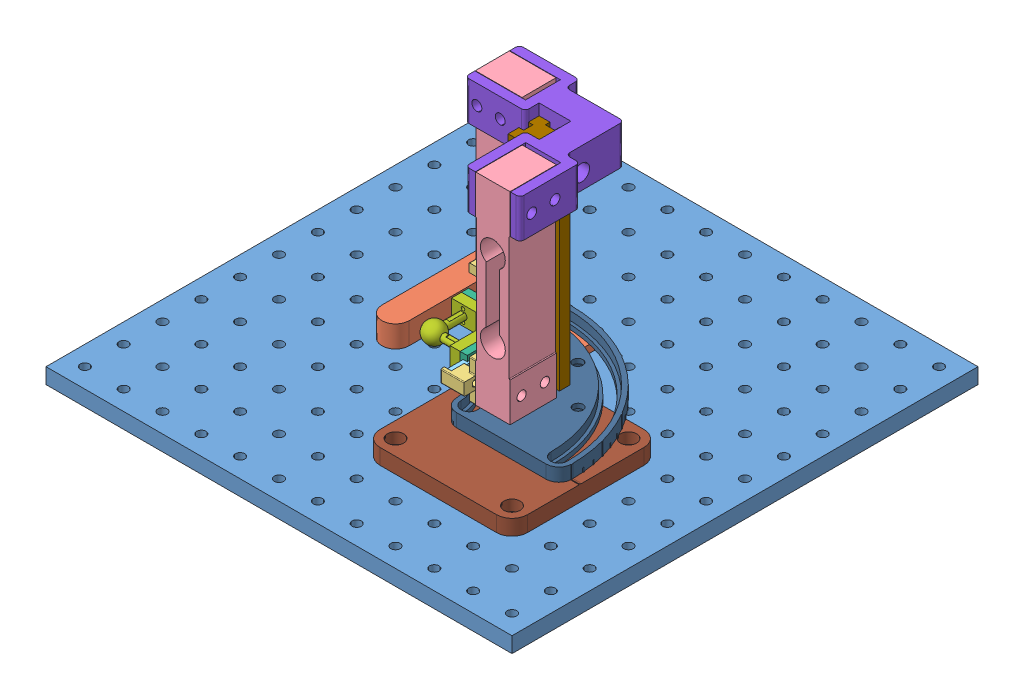
SolidWorks assembly ASM3, configuration 기본. Lengths in mm.
Overall size (300 175.5 300).
15 component instances, 11 part files, 49 mates.
Components (placement in the parent):
- platform-1: platform [기본] at (-708.9249 -138.0932 300) size (300 10 300)
- finger_model-1: finger_model [기본] at (-721.4249 -128.0932 287.5) size (60 55 113.75)
- linear_guide_holder_vertical_axis-1: linear_guide_holder_vertical_axis [기본] at (-705.2882 -80.0932 312.2502) x (0 1 0) z (0.00273 0 0.999996) size (25 45 15)
- Loadcell-1: Loadcell [기본] at (-720.3182 -27.5932 301.2911) x (0 1 0) z (0.999996 0 -0.00273) size (130 22 30)
- linear_guide_holder_vertical_axis-2: linear_guide_holder_vertical_axis [기본] at (-663.6751 -80.0932 353.6367) x (0 -1 0) z (-0.999996 0 0.00273) size (25 45 15)
- Loadcell-2: Loadcell [기본] at (-652.7161 -27.5932 338.6068) x (0 1 0) z (0.00273 0 0.999996) size (130 22 30)
- linear_guide_part1-1: linear_guide_part1 [기본] at (-678.175 -80.0932 353.6763) x (-0.00273 0 -0.999996) z (0 -1 0) size (40 4 5)
- linear_guide_part2-1: linear_guide_part2 [기본] at (-675.575 -80.0932 353.6692) x (0.00273 0 0.999996) z (0 -1 0) size (17 4.6 12)
- linear_guide_part1-2: linear_guide_part1 [기본] at (-705.2595 -80.0932 322.7501) x (-0.999996 0 0.00273) z (0 1 0) size (40 4 5)
- linear_guide_part2-2: linear_guide_part2 [기본] at (-705.2557 -80.0932 324.1501) x (0.999996 0 -0.00273) z (0 -1 0) size (17 4.6 12)
- contact_part_vertical-1: contact_part_vertical [기본] at (-705.1749 -80.0932 353.75) x (-0.999996 0 0.00273) z (0 1 0) size (33.5 33.5 13)
- Loadcell_holder_vertical_part1-1: Loadcell_holder_vertical_part1 [기본] at (-652.8184 12.4068 301.1069) x (-0.00273 0 -0.999996) z (0.999996 0 -0.00273) size (85 25 85)
- profile_20x20x140-1: profile_20x20x140 [기본] at (-671.5172 -109.5932 319.908) x (-0.00273 0 -0.999996) z (0.999996 0 -0.00273) size (20 140 20)
- rotary_guide_part1-1: rotary_guide_part1 [기본] at (-705.1749 -118.0932 353.75) x (-0.00273 0 -0.999996) z (0.999996 0 -0.00273) size (96.75 8.5 96.75)
- rotary_guide_part2-1: rotary_guide_part2 [기본] at (-705.1749 -128.0932 353.75) x (0 0 -1) z (1 0 0) size (95 10.5 95)
Mates (geometry in assembly coordinates):
- 동심1: concentric aligned: cylinder of platform-1 through (-696.4249 -128.0932 287.5) axis (0 -1 0) radius 3; cylinder of finger_model-1 through (-696.4249 -123.0932 287.5) axis (0 -1 0) radius 3
- 동심2: concentric aligned: cylinder of platform-1 through (-746.4249 -128.0932 287.5) axis (0 -1 0) radius 3; cylinder of finger_model-1 through (-746.4249 -123.0932 287.5) axis (0 -1 0) radius 3
- 일치1: coincident anti-aligned: plane of platform-1 through (-708.9249 -128.0932 300) normal (0 1 0); plane of finger_model-1 through (-721.4249 -128.0932 287.5) normal (0 -1 0)
- 일치2: coincident anti-aligned: plane of linear_guide_holder_vertical_axis-1 through (-705.2882 -80.0932 312.2502) normal (-0.00273 0 -0.999996); plane of Loadcell-1 through (-690.2883 -92.5932 312.2092) normal (0.00273 0 0.999996)
- 동심3: concentric anti-aligned: cylinder of linear_guide_holder_vertical_axis-1 through (-712.7773 -80.0932 316.2706) axis (-0.00273 0 -0.999996) radius 3.2; cylinder of Loadcell-1 through (-712.8714 -80.0932 281.7855) axis (0.00273 0 0.999996) radius 3
- 동심4: concentric anti-aligned: cylinder of linear_guide_holder_vertical_axis-1 through (-697.7773 -80.0932 316.2297) axis (-0.00273 0 -0.999996) radius 3.2; cylinder of Loadcell-1 through (-697.8714 -80.0932 281.7445) axis (0.00273 0 0.999996) radius 3
- 평행2: parallel anti-aligned: plane of platform-1 through (-708.9249 -128.0932 300) normal (0 1 0); plane of Loadcell-1 through (-690.2883 -92.5932 312.2092) normal (0 -1 0)
- 평행3: parallel anti-aligned: plane of platform-1 through (-708.9249 -128.0932 300) normal (0 1 0); plane of Loadcell-2 through (-663.6341 -92.5932 368.6367) normal (0 -1 0)
- 동심5: concentric anti-aligned: cylinder of linear_guide_holder_vertical_axis-2 through (-667.6546 -80.0932 361.1476) axis (0.999996 0 -0.00273) radius 3.2; cylinder of Loadcell-2 through (-633.1694 -80.0932 361.0535) axis (-0.999996 0 0.00273) radius 3
- 동심6: concentric anti-aligned: cylinder of linear_guide_holder_vertical_axis-2 through (-667.6955 -80.0932 346.1477) axis (0.999996 0 -0.00273) radius 3.2; cylinder of Loadcell-2 through (-633.2104 -80.0932 346.0535) axis (-0.999996 0 0.00273) radius 3
- 일치7: coincident anti-aligned: plane of linear_guide_holder_vertical_axis-2 through (-663.6751 -80.0932 353.6367) normal (0.999996 0 -0.00273); plane of Loadcell-2 through (-663.6341 -92.5932 368.6367) normal (-0.999996 0 0.00273)
- 동심7: concentric anti-aligned: cylinder of linear_guide_holder_vertical_axis-2 through (-674.216 -80.0932 338.6654) axis (0.999996 0 -0.00273) radius 1.15; cylinder of linear_guide_part1-1 through (-674.216 -80.0932 338.6654) axis (-0.999996 0 0.00273) radius 1.25
- 동심8: concentric anti-aligned: cylinder of linear_guide_holder_vertical_axis-2 through (-674.1341 -80.0932 368.6653) axis (0.999996 0 -0.00273) radius 1.15; cylinder of linear_guide_part1-1 through (-674.1341 -80.0932 368.6653) axis (-0.999996 0 0.00273) radius 1.25
- 일치8: coincident anti-aligned: plane of linear_guide_holder_vertical_axis-2 through (-674.175 -80.0932 353.6654) normal (-0.999996 0 0.00273); plane of linear_guide_part1-1 through (-674.175 -80.0932 353.6654) normal (0.999996 0 -0.00273)
- 너비1: width anti-aligned: plane of linear_guide_part2-1 through (-657.8319 -77.5932 362.1208) normal (0 -1 0); plane of linear_guide_part2-1 through (-657.8319 -82.5932 362.1208) normal (0 1 0); plane of linear_guide_part1-1 through (-674.2296 -77.5932 333.6655) normal (0 1 0); plane of linear_guide_part1-1 through (-674.2296 -82.5932 333.6655) normal (0 -1 0)
- 일치9: coincident anti-aligned: plane of linear_guide_part1-1 through (-678.175 -80.0932 353.6763) normal (-0.999996 0 0.00273); plane of linear_guide_part2-1 through (-678.175 -80.0932 353.6763) normal (0.999996 0 -0.00273)
- 거리 한도1: limit distance = 11.7 mm anti-aligned: plane of linear_guide_part2-1 through (-680.1518 -74.0932 362.1817) normal (0.00273 0 0.999996); plane of linear_guide_holder_vertical_axis-2 through (-678.6199 -76.0932 373.8776) normal (-0.00273 0 -0.999996)
- 거리 한도2: limit distance = 11.7 mm anti-aligned: plane of linear_guide_holder_vertical_axis-2 through (-678.7302 -76.0932 333.4777) normal (0.00273 0 0.999996); plane of linear_guide_part2-1 through (-680.1982 -74.0932 345.1818) normal (-0.00273 0 -0.999996)
- 일치11: coincident anti-aligned: plane of linear_guide_holder_vertical_axis-1 through (-705.2595 -80.0932 322.7501) normal (0.00273 0 0.999996); plane of linear_guide_part1-2 through (-705.2595 -80.0932 322.7501) normal (-0.00273 0 -0.999996)
- 동심9: concentric aligned: cylinder of linear_guide_holder_vertical_axis-1 through (-690.2596 -80.0932 322.7092) axis (-0.00273 0 -0.999996) radius 1.15; cylinder of linear_guide_part1-2 through (-690.2487 -80.0932 326.7092) axis (-0.00273 0 -0.999996) radius 1.25
- 동심10: concentric aligned: cylinder of linear_guide_holder_vertical_axis-1 through (-720.2595 -80.0932 322.7911) axis (-0.00273 0 -0.999996) radius 1.15; cylinder of linear_guide_part1-2 through (-720.2486 -80.0932 326.791) axis (-0.00273 0 -0.999996) radius 1.25
- 일치12: coincident anti-aligned: plane of linear_guide_part1-2 through (-705.2486 -80.0932 326.7501) normal (0.00273 0 0.999996); plane of linear_guide_part2-2 through (-705.2486 -80.0932 326.7501) normal (-0.00273 0 -0.999996)
- 거리 한도3: limit distance = 11.7 mm anti-aligned: plane of linear_guide_holder_vertical_axis-1 through (-685.0473 -84.0932 327.195) normal (-0.999996 0 0.00273); plane of linear_guide_part2-2 through (-696.7432 -74.0932 328.7269) normal (0.999996 0 -0.00273)
- 거리 한도4: limit distance = 11.7 mm anti-aligned: plane of linear_guide_holder_vertical_axis-1 through (-725.4472 -84.0932 327.3052) normal (0.999996 0 -0.00273); plane of linear_guide_part2-2 through (-713.7431 -74.0932 328.7733) normal (-0.999996 0 0.00273)
- 일치13: coincident anti-aligned: plane of linear_guide_part2-2 through (-705.2432 -80.0932 328.7501) normal (0.00273 0 0.999996); plane of contact_part_vertical-1 through (-705.2432 -80.0932 328.7501) normal (-0.00273 0 -0.999996)
- 동심11: concentric anti-aligned: cylinder of linear_guide_part2-2 through (-705.2486 -83.8432 326.7501) axis (0.00273 0 0.999996) radius 1; cylinder of contact_part_vertical-1 through (-705.2254 -83.8432 335.2501) axis (-0.00273 0 -0.999996) radius 1.15
- 동심12: concentric anti-aligned: cylinder of linear_guide_part2-2 through (-705.2486 -76.3432 326.7501) axis (0.00273 0 0.999996) radius 1; cylinder of contact_part_vertical-1 through (-705.2254 -76.3432 335.2501) axis (-0.00273 0 -0.999996) radius 1.15
- 동심13: concentric anti-aligned: cylinder of linear_guide_part2-1 through (-678.175 -76.3432 353.6763) axis (-0.999996 0 0.00273) radius 1; cylinder of contact_part_vertical-1 through (-686.675 -76.3432 353.6995) axis (0.999996 0 -0.00273) radius 1.15
- 동심14: concentric anti-aligned: cylinder of linear_guide_part2-1 through (-678.175 -83.8432 353.6763) axis (-0.999996 0 0.00273) radius 1; cylinder of contact_part_vertical-1 through (-686.675 -83.8432 353.6995) axis (0.999996 0 -0.00273) radius 1.15
- 일치14: coincident anti-aligned: plane of linear_guide_part2-1 through (-680.175 -80.0932 353.6818) normal (-0.999996 0 0.00273); plane of contact_part_vertical-1 through (-680.175 -80.0932 353.6818) normal (0.999996 0 -0.00273)
- 너비5: width anti-aligned: plane of Loadcell_holder_vertical_part1-1 through (-690.349 37.4068 289.9593) normal (0.00273 0 0.999996); plane of Loadcell_holder_vertical_part1-1 through (-720.2875 37.4068 312.5411) normal (-0.00273 0 -0.999996); plane of Loadcell-1 through (-690.3483 12.4068 290.2093) normal (-0.00273 0 -0.999996); plane of Loadcell-1 through (-690.2883 12.4068 312.2092) normal (0.00273 0 0.999996)
- 동심15: concentric anti-aligned: cylinder of Loadcell-1 through (-712.8714 24.9068 281.7855) axis (0.00273 0 0.999996) radius 3; cylinder of Loadcell_holder_vertical_part1-1 through (-712.7457 24.9068 327.8215) axis (-0.00273 0 -0.999996) radius 3.2
- 동심16: concentric anti-aligned: cylinder of Loadcell-1 through (-697.8714 24.9068 281.7445) axis (0.00273 0 0.999996) radius 3; cylinder of Loadcell_holder_vertical_part1-1 through (-697.7458 24.9068 327.7806) axis (-0.00273 0 -0.999996) radius 3.2
- 너비6: width aligned: plane of Loadcell-2 through (-641.6342 12.4068 368.5766) normal (0.999996 0 -0.00273); plane of Loadcell-2 through (-663.6341 12.4068 368.6367) normal (-0.999996 0 0.00273); plane of Loadcell_holder_vertical_part1-1 through (-663.966 37.4068 338.6375) normal (0.999996 0 -0.00273); plane of Loadcell_holder_vertical_part1-1 through (-641.3842 37.4068 368.5759) normal (-0.999996 0 0.00273)
- 동심17: concentric anti-aligned: cylinder of Loadcell-2 through (-633.2104 24.9068 346.0535) axis (-0.999996 0 0.00273) radius 3; cylinder of Loadcell_holder_vertical_part1-1 through (-679.2465 24.9068 346.1792) axis (0.999996 0 -0.00273) radius 3.2
- 동심18: concentric anti-aligned: cylinder of Loadcell-2 through (-633.1694 24.9068 361.0535) axis (-0.999996 0 0.00273) radius 3; cylinder of Loadcell_holder_vertical_part1-1 through (-679.2055 24.9068 361.1791) axis (0.999996 0 -0.00273) radius 3.2
- 너비7: width aligned: plane of finger_model-1 through (-721.4249 -73.0932 287.5) normal (0 1 0); plane of finger_model-1 through (-721.4249 -87.0932 287.5) normal (0 -1 0); plane of contact_part_vertical-1 through (-713.7254 -74.0932 335.2733) normal (0 1 0); plane of contact_part_vertical-1 through (-713.7254 -86.0932 335.2733) normal (0 -1 0)
- 너비10: width anti-aligned: plane of Loadcell_holder_vertical_part1-1 through (-681.745 -53.2834 309.7359) normal (0.999996 0 -0.00273); plane of Loadcell_holder_vertical_part1-1 through (-661.3451 -53.2834 309.6802) normal (-0.999996 0 0.00273); plane of profile_20x20x140-1 through (-681.5253 30.4068 316.9353) normal (-0.999996 0 0.00273); plane of profile_20x20x140-1 through (-661.5254 30.4068 316.8807) normal (0.999996 0 -0.00273)
- 일치19: coincident anti-aligned: plane of profile_20x20x140-1 through (-671.5172 -109.5932 319.908) normal (0 -1 0); plane of rotary_guide_part1-1 through (-705.2363 -109.5932 331.2501) normal (0 1 0)
- 너비11: width aligned: plane of profile_20x20x140-1 through (-681.5444 30.4068 309.9353) normal (-0.00273 0 -0.999996); plane of profile_20x20x140-1 through (-681.4898 30.4068 329.9353) normal (0.00273 0 0.999996); plane of Loadcell_holder_vertical_part1-1 through (-661.2894 -53.2834 330.0801) normal (-0.00273 0 -0.999996); plane of Loadcell_holder_vertical_part1-1 through (-661.3451 -53.2834 309.6802) normal (0.00273 0 0.999996)
- 너비12: width: plane of profile_20x20x140-1 through (-674.5445 30.4068 309.9162) normal (0.999996 0 -0.00273); plane of profile_20x20x140-1 through (-668.5445 30.4068 309.8998) normal (-0.999996 0 0.00273); cylinder of rotary_guide_part1-1 through (-671.5854 -109.5932 294.9081) axis (0 -1 0) radius 3.2
- 너비13: width: plane of profile_20x20x140-1 through (-661.509 30.4068 322.8807) normal (-0.00273 0 -0.999996); plane of profile_20x20x140-1 through (-661.5254 30.4068 316.8807) normal (0.00273 0 0.999996); cylinder of rotary_guide_part1-1 through (-646.5173 -109.5932 319.8398) axis (0 -1 0) radius 3.2
- 너비15: width: plane of profile_20x20x140-1 through (-674.4899 30.4068 329.9162) normal (0.999996 0 -0.00273); plane of profile_20x20x140-1 through (-668.4899 30.4068 329.8998) normal (-0.999996 0 0.00273); cylinder of rotary_guide_part1-1 through (-671.4489 -109.5932 344.9079) axis (0 -1 0) radius 3.2
- 일치23: coincident anti-aligned: plane of platform-1 through (-708.9249 -128.0932 300) normal (0 1 0); plane of rotary_guide_part2-1 through (-705.1749 -128.0932 353.75) normal (0 -1 0)
- 일치24: coincident anti-aligned: plane of rotary_guide_part1-1 through (-705.2363 -118.0932 331.2501) normal (0 -1 0); plane of rotary_guide_part2-1 through (-705.1749 -118.0932 353.75) normal (0 1 0)
- 탄젠트4: tangent aligned: cylinder of rotary_guide_part1-1 through (-705.1749 -109.5932 353.75) axis (0 -1 0) radius 25.75; cylinder of rotary_guide_part2-1 through (-682.6749 -137.2856 353.75) axis (0 1 0) radius 3.25
- 동심41: concentric aligned: cylinder of platform-1 through (-696.4249 -128.0932 312.5) axis (0 -1 0) radius 3; cylinder of rotary_guide_part2-1 through (-696.4249 -118.0932 312.5) axis (0 -1 0) radius 3.2
- 탄젠트6: tangent aligned: cylinder of rotary_guide_part1-1 through (-705.1749 -109.5932 353.75) axis (0 -1 0) radius 83.25; cylinder of rotary_guide_part2-1 through (-625.1749 -137.2856 353.75) axis (0 1 0) radius 3.25
- 동심42: concentric aligned: cylinder of platform-1 through (-696.4249 -128.0932 387.5) axis (0 -1 0) radius 3; cylinder of rotary_guide_part2-1 through (-696.4249 -118.0932 387.5) axis (0 -1 0) radius 3.2
